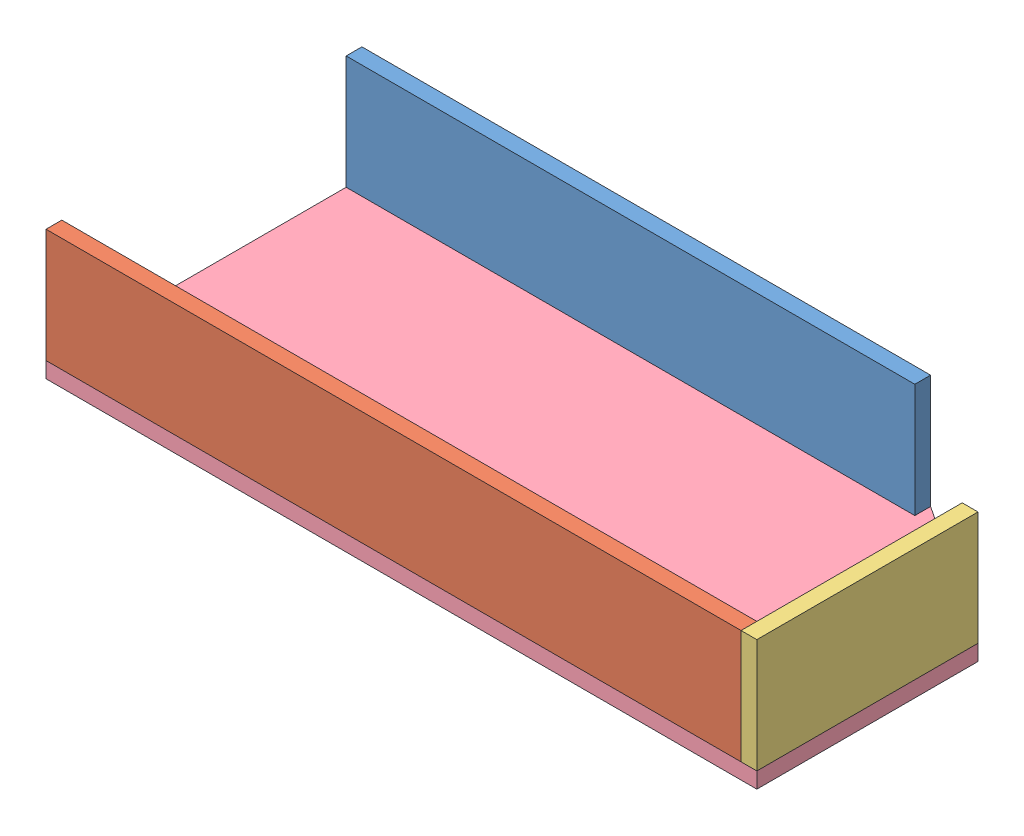
SolidWorks assembly BatteryCaseLAssem, configuration Default. Lengths in mm.
Overall size (142.88 26.04 63.5).
6 component instances, 6 part files, 9 mates.
Components (placement in the parent):
- BatteryCaseShort-1: BatteryCaseShort [Default] at (-92.8619 -9.4041 55.3909) size (114.3 22.86 3.17)
- BatteryCaseLong-1: BatteryCaseLong [Default] at (-80.1619 -9.4041 115.7159) size (139.7 22.86 3.17)
- BatteryCaseEnd-1: BatteryCaseEnd [Default] at (-8.7244 -9.4041 95.0784) x (0 0 1) z (0 -1 0) size (44.45 3.17 22.86)
- Part7^BatteryCaseLAssem-1: Part7^BatteryCaseLAssem [Default] at origin (virtual)
- Part8^BatteryCaseLAssem-1: Part8^BatteryCaseLAssem [Default] at origin (virtual)
- Part9-1: Part9 [Default] at (0 -22.4216 0) x (1 0 0) z (0 1 0) size (142.88 63.5 3.17)
Mates (geometry in assembly coordinates):
- Coincident1: coincident anti-aligned: plane of BatteryCaseLong-1 through (-10.3119 -20.8341 117.3034) normal (1 0 0); plane of BatteryCaseEnd-1 through (-10.3119 -9.4041 95.0784) normal (-1 0 0)
- Coincident2: coincident aligned: plane of BatteryCaseLong-1 through (-80.1619 -9.4041 117.3034) normal (0 0 1); plane of BatteryCaseEnd-1 through (-10.3119 -20.8341 117.3034) normal (0 0 1)
- Coincident4: coincident aligned: plane of BatteryCaseLong-1 through (-150.0119 2.0259 117.3034) normal (0 1 0); plane of BatteryCaseEnd-1 through (-10.3119 2.0259 72.8534) normal (0 1 0)
- Coincident5: coincident aligned: plane of BatteryCaseShort-1 through (-150.0119 -20.8341 56.9784) normal (-1 0 0); plane of BatteryCaseLong-1 through (-150.0119 -20.8341 117.3034) normal (-1 0 0)
- Coincident7: coincident aligned: plane of BatteryCaseShort-1 through (-150.0119 2.0259 56.9784) normal (0 1 0); plane of BatteryCaseEnd-1 through (-10.3119 2.0259 72.8534) normal (0 1 0)
- Distance1: distance = 63.5 mm anti-aligned: plane of BatteryCaseLong-1 through (-80.1619 -9.4041 117.3034) normal (0 0 1); plane of BatteryCaseShort-1 through (-92.8619 -9.4041 53.8034) normal (0 0 -1)
- Coincident13: coincident anti-aligned: plane of Part9-1 through (0 5.2009 0) normal (0 1 0); plane of BatteryCaseShort-1 through (-150.0119 -20.8341 56.9784) normal (0 -1 0)
- Coincident14: coincident aligned: plane of BatteryCaseEnd-1 through (-7.1369 -9.4041 95.0784) normal (1 0 0); plane of Part9-1 through (-7.1369 5.2009 117.3034) normal (1 0 0)
- Coincident15: coincident aligned: plane of BatteryCaseLong-1 through (-80.1619 -9.4041 117.3034) normal (0 0 1); plane of Part9-1 through (-150.0119 5.2009 117.3034) normal (0 0 1)
